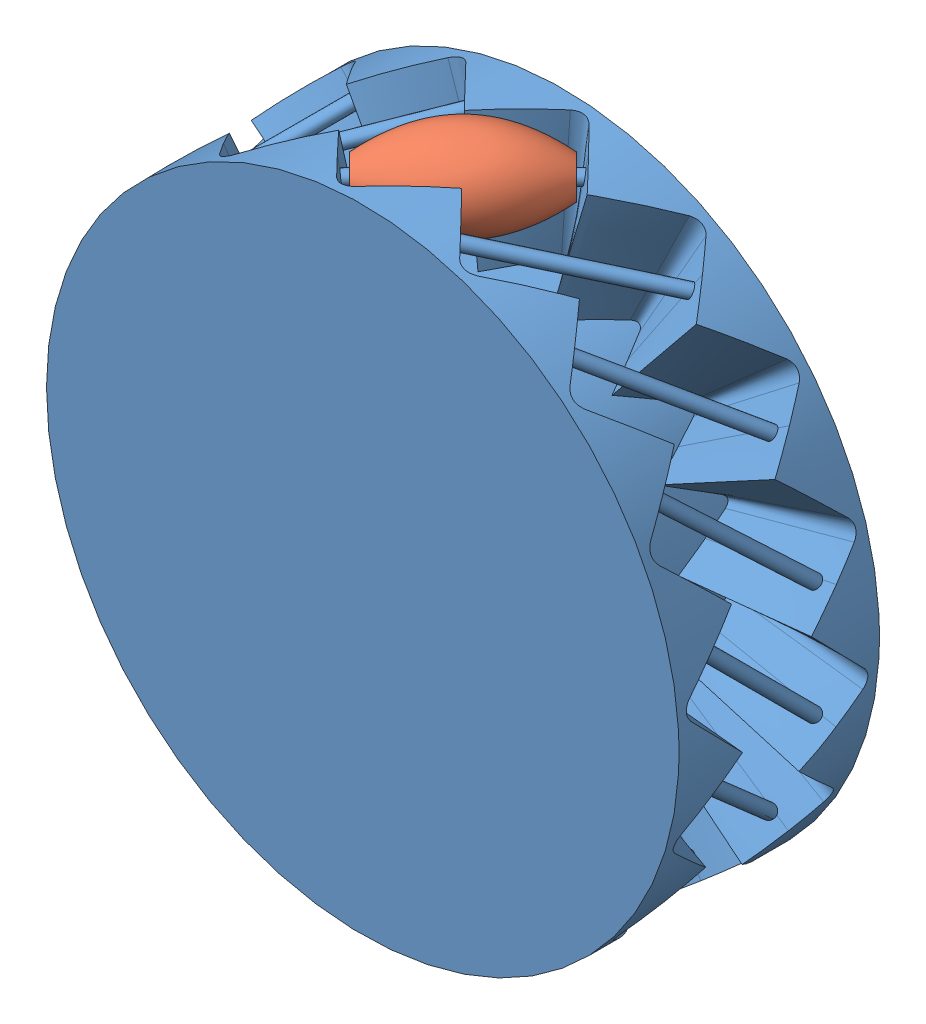
SolidWorks assembly 麦克纳姆轮实验室款, configuration 默认. Lengths in mm.
Overall size (142.16 158.52 45).
2 component instances, 2 part files, 1 mates.
Components (placement in the parent):
- 麦克纳姆轮-1: 麦克纳姆轮 [默认] at (59.0104 77.0756 89.8589) size (142.16 158.52 45)
- 橡胶滚子-1: 橡胶滚子 [默认] at (72.9074 142.1752 98.4619) x (0.707107 0 -0.707107) z (0.705783 0.061173 0.705783) size (36 20 20)
Mates (geometry in assembly coordinates):
- 同心1: concentric anti-aligned: cylinder of 麦克纳姆轮-1 through (76.6881 142.1752 94.6812) axis (-0.707107 0 0.707107) radius 1.5; cylinder of 橡胶滚子-1 through (39.9156 142.1752 131.4538) axis (0.707107 0 -0.707107) radius 1.5
